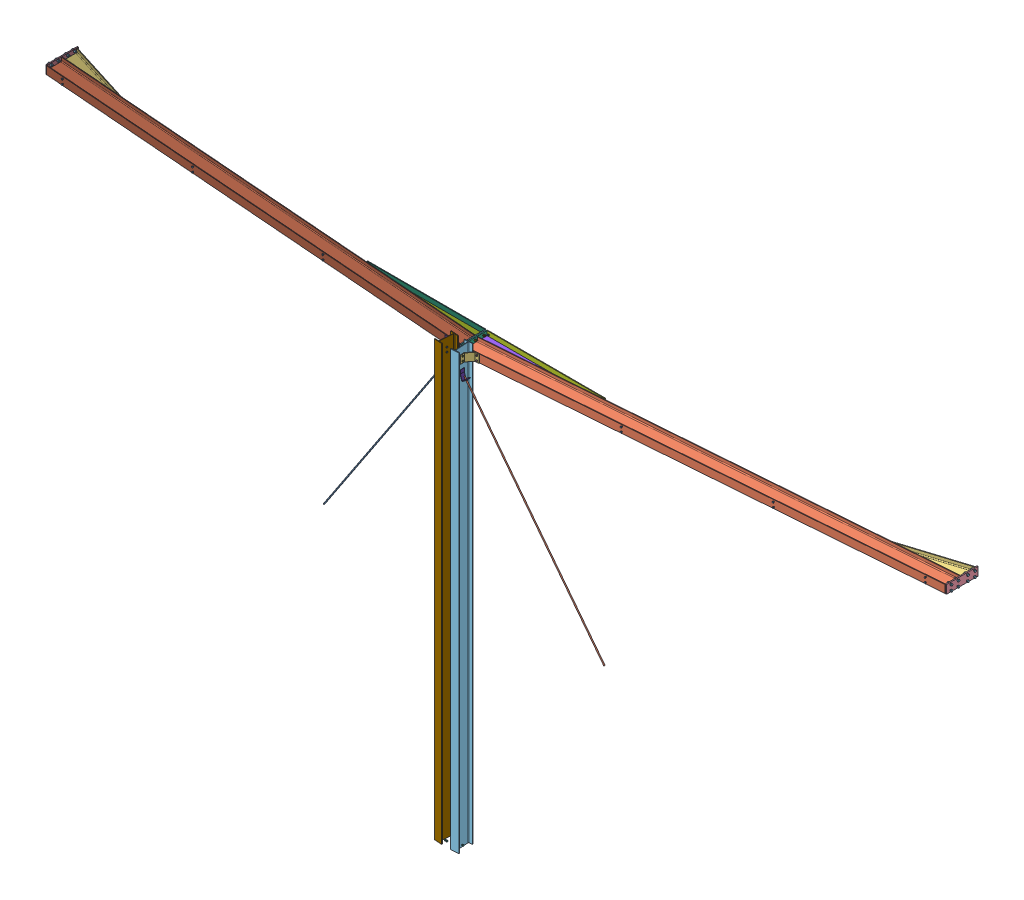
SolidWorks assembly DETAIL pannes, configuration Défaut. Lengths in mm.
Overall size (12852.89 6190.97 1156.65).
67 component instances, 28 part files, 0 mates.
Components (placement in the parent):
- Undefined-1: Undefined [Défaut] at origin size (12852.89 6190.97 1156.65)
  - Undefined1-1: Undefined1 [Défaut] at origin size (12852.89 6190.97 1156.65)
    - Undefined2-1: Undefined2 [Défaut] at origin size (12852.89 6190.97 1156.65)
      - Undefined3-1: Undefined3 [Défaut] at origin size (12852.89 6190.97 1156.65)
        - IfcElementAssembly_Steel Assembly-1: IfcElementAssembly_Steel Assembly [Défaut] at origin size (25.17 85 44.56)
          - Part0-1: Part0 [Défaut] at (387.3827 23967.5 4629.7987) x (-0.997054 0 -0.076696) z (0 -1 0) size (21.94 43 20)
          - Part0-2: Part0 [Défaut] at (387.3827 24032.5 4629.7987) x (-0.997054 0 -0.076696) z (0 -1 0) size (21.94 43 20)
        - IfcElementAssembly_Steel Assembly4-1: IfcElementAssembly_Steel Assembly4 [Défaut] at origin size (25.17 85 44.56)
          - Part0-1: Part0 [Défaut] at (2387.3827 23967.5 4783.6448) x (-0.997054 0 -0.076696) z (0 -1 0) size (21.94 43 20)
          - Part0-2: Part0 [Défaut] at (2387.3827 24032.5 4783.6448) x (-0.997054 0 -0.076696) z (0 -1 0) size (21.94 43 20)
        - IfcElementAssembly_Steel Assembly5-1: IfcElementAssembly_Steel Assembly5 [Défaut] at origin size (25.17 85 44.56)
          - Part0-1: Part0 [Défaut] at (4387.3827 23967.5 4937.491) x (-0.997054 0 -0.076696) z (0 -1 0) size (21.94 43 20)
          - Part0-2: Part0 [Défaut] at (4387.3827 24032.5 4937.491) x (-0.997054 0 -0.076696) z (0 -1 0) size (21.94 43 20)
        - IfcElementAssembly_Steel Assembly6-1: IfcElementAssembly_Steel Assembly6 [Défaut] at origin size (25.17 85 44.56)
          - Part0-1: Part0 [Défaut] at (8612.6173 24032.5 4937.491) x (0.997054 0 -0.076696) z (0 1 0) size (21.94 43 20)
          - Part0-2: Part0 [Défaut] at (8612.6173 23967.5 4937.491) x (0.997054 0 -0.076696) z (0 1 0) size (21.94 43 20)
        - IfcElementAssembly_Steel Assembly7-1: IfcElementAssembly_Steel Assembly7 [Défaut] at origin size (25.17 85 44.56)
          - Part0-1: Part0 [Défaut] at (10612.6173 24032.5 4783.6448) x (0.997054 0 -0.076696) z (0 1 0) size (21.94 43 20)
          - Part0-2: Part0 [Défaut] at (10612.6173 23967.5 4783.6448) x (0.997054 0 -0.076696) z (0 1 0) size (21.94 43 20)
        - IfcElementAssembly_Steel Assembly8-1: IfcElementAssembly_Steel Assembly8 [Défaut] at origin size (25.17 85 44.56)
          - Part0-1: Part0 [Défaut] at (12612.6173 24032.5 4629.7987) x (0.997054 0 -0.076696) z (0 1 0) size (21.94 43 20)
          - Part0-2: Part0 [Défaut] at (12612.6173 23967.5 4629.7987) x (0.997054 0 -0.076696) z (0 1 0) size (21.94 43 20)
        - IfcElementAssembly_Steel Assembly9-1: IfcElementAssembly_Steel Assembly9 [Défaut] at origin size (6451.44 130 948.27)
          - POUTRE1-1: POUTRE1 [Défaut] at (6491.5634 24000 4990.324) x (0.997054 0 -0.076696) z (0.076696 0 0.997054) size (6385.68 110 220)
          - Part1-1: Part1 [Défaut] at (12897.9513 24000 4279.6916) x (-0.954078 0 0.299557) z (0.299557 0 0.954078) size (950.59 110 205.12)
          - Part2-1: Part2 [Défaut] at (12872.5 24000 4159.2308) x (0 0 1) z (1 0 0) size (445 120 15)
          - Part3-1: Part3 [Défaut] at (12880 24000 4549.2308) x (0 0 -1) z (0 1 0) size (366.18 60 105)
          - Part4-1: Part4 [Défaut] at (6507.5 24000 5107.5) x (0 0 -1) z (-1 0 0) size (359.82 130 15)
          - Part5-1: Part5 [Défaut] at (6515 24000 4744.675) x (1 0 0) z (0 0 -1) size (1670.78 130 10)
          - Part6-1: Part6 [Défaut] at (6515 24000 4814.675) x (1 0 0) z (0 -1 0) size (1670.78 128.52 6)
          - Part7-1: Part7 [Défaut] at (6500 24000 5050) x (0 0 -1) z (0 -1 0) size (277.71 65 95)
          - Part8-1: Part8 [Défaut] at (6538 24000 4729.675) x (-1 0 0) z (0 1 0) size (21.94 48 70)
        - IfcElementAssembly_Steel Assembly10-1: IfcElementAssembly_Steel Assembly10 [Défaut] at origin size (6475.41 130 948.27)
          - POUTRE-1: POUTRE [Défaut] at (8.4366 24000 4490.324) x (0.997054 0 0.076696) z (-0.076696 0 0.997054) size (6385.68 110 220)
          - Part9-1: Part9 [Défaut] at (102.0487 24000 4279.6916) x (0.954078 0 0.299557) z (-0.299557 0 0.954078) size (950.59 110 205.12)
          - Part10-1: Part10 [Défaut] at (127.5 24000 4159.2308) x (0 0 1) z (1 0 0) size (445 120 15)
          - Part3-1: Part3 [Défaut] at (120 24000 4549.2308) x (0 0 -1) z (0 -1 0) size (366.18 60 105)
          - Part11-1: Part11 [Défaut] at (6492.5 24000 5107.5) x (0 0 -1) z (-1 0 0) size (359.82 130 15)
          - Part12-1: Part12 [Défaut] at (4814.2245 24000 4744.675) x (1 0 0) z (0 0 -1) size (1670.78 130 10)
          - Part13-1: Part13 [Défaut] at (4814.2245 24000 4814.675) x (1 0 0) z (0 -1 0) size (1670.78 128.52 6)
          - Part8-1: Part8 [Défaut] at (6538 24000 4729.675) x (-1 0 0) z (0 1 0) size (21.94 48 70)
        - IfcElementAssembly_Steel Assembly11-1: IfcElementAssembly_Steel Assembly11 [Défaut] at origin size (94.99 129.63 66.78)
          - ATTACHE2-1: ATTACHE2 [Défaut] at (6613.8706 23870.8667 5201.5657) x (0 -1 0) z (0.076696 0 0.997054) size (129.63 90.65 60)
        - IfcElementAssembly_Steel Assembly12-1: IfcElementAssembly_Steel Assembly12 [Défaut] at origin size (94.99 129.63 66.78)
          - ATTACHE-1: ATTACHE [Défaut] at (6386.1294 23870.8667 5201.5657) x (0 -1 0) z (-0.076696 0 0.997054) size (129.63 90.65 60)
        - IfcElementAssembly_Steel Assembly13-1: IfcElementAssembly_Steel Assembly13 [Défaut] at origin size (1859.31 2719.64 156.9)
          - BRETELLE THREAD60MM3-1: BRETELLE THREAD60MM3 [Défaut] at (6360.8959 23804.9672 5199.6246) x (-0.56235 -0.825767 -0.043258) z (0.076696 0 -0.997054) size (3283.91 14 14)
        - IfcElementAssembly_Steel Assembly14-1: IfcElementAssembly_Steel Assembly14 [Défaut] at origin size (1855.12 2713.5 156.58)
          - BRETELLE THREAD60MM-1: BRETELLE THREAD60MM [Défaut] at (6643.2902 23798.8202 5199.3026) x (0.56235 -0.825767 -0.043258) z (-0.076696 0 -0.997054) size (3276.47 14 14)
        - IfcElementAssembly_Steel Assembly15-1: IfcElementAssembly_Steel Assembly15 [Défaut] at origin size (150.33 110 175.79)
          - ECHANTIGNOLLE4-1: ECHANTIGNOLLE4 [Défaut] at (6742.8357 24000 5085.3321) x (-0.997054 0 0.076696) z (0 -1 0) size (140 140 110)
          - Part14-1: Part14 [Défaut] at (6712.6173 23967.5 5083.6448) x (0.997054 0 -0.076696) z (0 1 0) size (21.94 43 19)
          - Part14-2: Part14 [Défaut] at (6712.6173 24032.5 5083.6448) x (0.997054 0 -0.076696) z (0 1 0) size (21.94 43 19)
        - IfcElementAssembly_Steel Assembly16-1: IfcElementAssembly_Steel Assembly16 [Défaut] at origin size (126.55 6145 227.79)
          - PANNE5-1: PANNE5 [Défaut] at (6608.4366 18000 5201.9837) x (0 1 0) z (0.076696 0 0.997054) size (6145 110 220)
          - Part15-1: Part15 [Défaut] at (6608.4366 18000 5201.9837) x (0 1 0) z (-0.076696 0 -0.997054) size (21.94 38 19)
          - Part16-1: Part16 [Défaut] at (6608.4366 23970 5201.9837) x (0 -1 0) z (-0.076696 0 -0.997054) size (21.94 38 19)
          - Part16-2: Part16 [Défaut] at (6608.4366 24030 5201.9837) x (0 -1 0) z (-0.076696 0 -0.997054) size (21.94 38 19)
        - IfcElementAssembly_Steel Assembly17-1: IfcElementAssembly_Steel Assembly17 [Défaut] at origin size (150.33 110 175.79)
          - ECHANTIGNOLLE-1: ECHANTIGNOLLE [Défaut] at (6257.1643 24000 5085.3321) x (0.997054 0 0.076696) z (0 1 0) size (140 140 110)
          - Part14-1: Part14 [Défaut] at (6287.3827 24032.5 5083.6448) x (-0.997054 0 -0.076696) z (0 -1 0) size (21.94 43 19)
          - Part14-2: Part14 [Défaut] at (6287.3827 23967.5 5083.6448) x (-0.997054 0 -0.076696) z (0 -1 0) size (21.94 43 19)
        - IfcElementAssembly_Steel Assembly18-1: IfcElementAssembly_Steel Assembly18 [Défaut] at origin size (126.55 6190.97 227.79)
          - PANNE-1: PANNE [Défaut] at (6391.5634 24150 5201.9837) x (0 -1 0) z (-0.076696 0 0.997054) size (6145 110 220)
          - Part15-1: Part15 [Défaut] at (6391.5634 18000 5201.9837) x (0 -1 0) z (0.076696 0 -0.997054) size (21.94 38 19)
          - Part17-1: Part17 [Défaut] at (6391.5634 23970 5201.9837) x (0 -1 0) z (0.076696 0 -0.997054) size (21.94 38 19)
          - Part17-2: Part17 [Défaut] at (6391.5634 24030 5201.9837) x (0 -1 0) z (0.076696 0 -0.997054) size (21.94 38 19)
